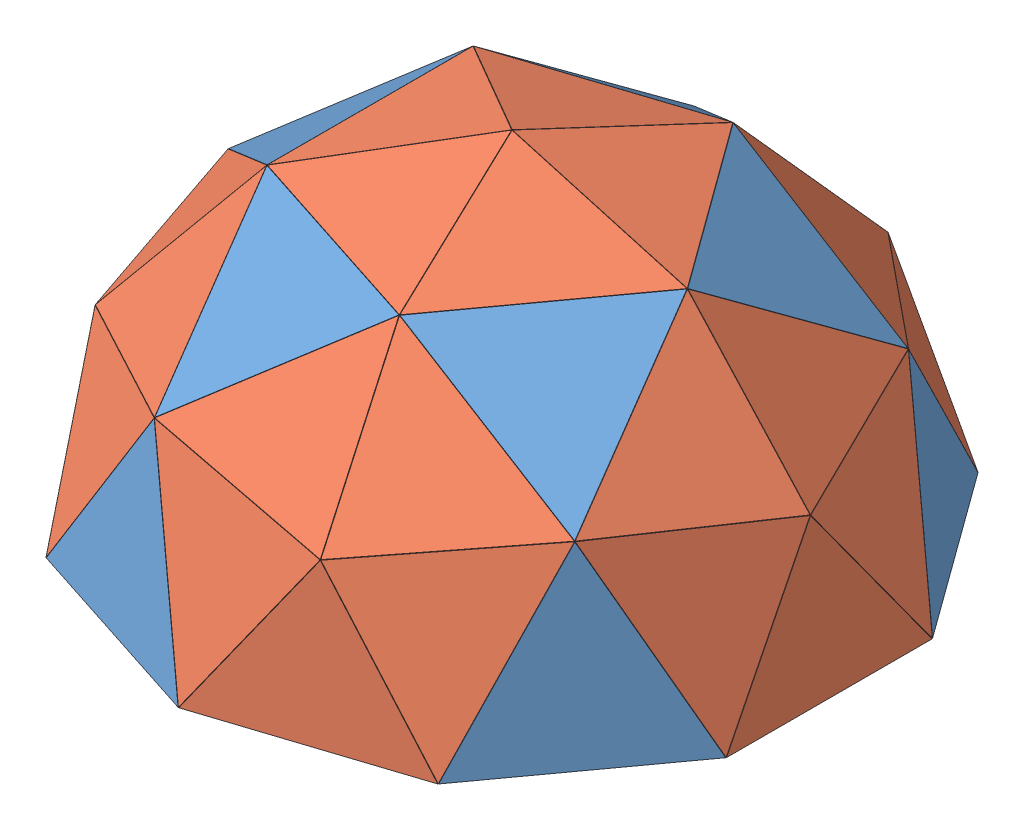
SolidWorks assembly AS_APPOLO1, configuration По умолчанию. Lengths in mm.
Overall size (616.24 389.86 611.38).
40 component instances, 2 part files, 25 mates.
Components (placement in the parent):
- d1^AS_APPOLO1-1: d1^AS_APPOLO1 [По умолчанию] at (-85.0651 52.5731 261.8034) x (-0.952822 -0.059759 -0.29759) z (0.303531 -0.187592 -0.934172) size (185.07 165.91 1) (virtual)
- d2^AS_APPOLO1-1: d2^AS_APPOLO1 [По умолчанию] at (75.8691 267.0702 55.1221) x (-0.963409 0.262502 0.054179) z (-0.268035 -0.943522 -0.194739) size (163.71 155.96 1) (virtual)
- d2^AS_APPOLO1-2: d2^AS_APPOLO1 [По умолчанию] at (-28.9794 267.0702 89.1894) x (-0.349237 0.262502 -0.899514) z (0.10238 -0.943522 -0.315094) size (163.71 155.96 1) (virtual)
- d2^AS_APPOLO1-3: d2^AS_APPOLO1 [По умолчанию] at (-93.7793 267.0702 0) x (0.747569 0.262502 -0.61011) z (0.331309 -0.943522 0) size (163.71 155.96 1) (virtual)
- d2^AS_APPOLO1-4: d2^AS_APPOLO1 [По умолчанию] at (-28.9794 267.0702 -89.1894) x (0.81126 0.262502 0.522446) z (0.10238 -0.943522 0.315094) size (163.71 155.96 1) (virtual)
- d2^AS_APPOLO1-5: d2^AS_APPOLO1 [По умолчанию] at (75.8691 267.0702 -55.1221) x (-0.246182 0.262502 0.932999) z (-0.268035 -0.943522 0.194739) size (163.71 155.96 1) (virtual)
- d1^AS_APPOLO1-2: d1^AS_APPOLO1 [По умолчанию] at (-275.2764 52.5731 0) x (-0.011413 -0.059759 -0.998148) z (0.982247 -0.187592 0) size (185.07 165.91 1) (virtual)
- d1^AS_APPOLO1-3: d1^AS_APPOLO1 [По умолчанию] at (-85.0651 52.5731 -261.8034) x (0.945768 -0.059759 -0.319299) z (0.303531 -0.187592 0.934172) size (185.07 165.91 1) (virtual)
- d1^AS_APPOLO1-4: d1^AS_APPOLO1 [По умолчанию] at (222.7033 52.5731 -161.8034) x (0.59593 -0.059759 0.80081) z (-0.794654 -0.187592 0.57735) size (185.07 165.91 1) (virtual)
- d1^AS_APPOLO1-5: d1^AS_APPOLO1 [По умолчанию] at (222.7033 52.5731 161.8034) x (-0.577463 -0.059759 0.814227) z (-0.794654 -0.187592 -0.57735) size (185.07 165.91 1) (virtual)
- d1^AS_APPOLO1-6: d1^AS_APPOLO1 [По умолчанию] at (-52.5731 222.7033 161.8034) x (0.964235 0.036933 0.262464) z (0.187592 -0.794654 -0.57735) size (185.07 165.91 1) (virtual)
- d2^AS_APPOLO1-6: d2^AS_APPOLO1 [По умолчанию] at (-7.0029 93.5175 267.0702) x (0.457316 0.843008 -0.283197) z (0.02474 -0.330384 -0.943522) size (163.71 155.96 1) (virtual)
- d2^AS_APPOLO1-7: d2^AS_APPOLO1 [По умолчанию] at (162.6454 93.5175 211.9481) x (-0.734672 -0.194973 0.649802) z (-0.574604 -0.330384 -0.748783) size (163.71 155.96 1) (virtual)
- d2^AS_APPOLO1-8: d2^AS_APPOLO1 [По умолчанию] at (86.7764 35.5587 267.0702) x (-0.611006 0.78604 0.093872) z (-0.306569 -0.125624 -0.943522) size (163.71 155.96 1) (virtual)
- d2^AS_APPOLO1-9: d2^AS_APPOLO1 [По умолчанию] at (10.9073 187.2968 211.9481) x (0.99391 -0.102798 0.039693) z (-0.038534 -0.661694 -0.748783) size (163.71 155.96 1) (virtual)
- d2^AS_APPOLO1-10: d2^AS_APPOLO1 [По умолчанию] at (115.7558 187.2968 177.8808) x (0.257221 -0.744305 0.616318) z (-0.408949 -0.661694 -0.628428) size (163.71 155.96 1) (virtual)
- d2^AS_APPOLO1-11: d2^AS_APPOLO1 [По умолчанию] at (-256.1629 93.5175 75.8691) x (0.410654 0.843008 0.347421) z (0.904988 -0.330384 -0.268035) size (163.71 155.96 1) (virtual)
- d2^AS_APPOLO1-12: d2^AS_APPOLO1 [По умолчанию] at (-151.3145 93.5175 -220.1806) x (-0.203517 0.843008 0.497914) z (0.534573 -0.330384 0.777868) size (163.71 155.96 1) (virtual)
- d2^AS_APPOLO1-13: d2^AS_APPOLO1 [По умолчанию] at (162.6454 93.5175 -211.9481) x (-0.536435 0.843008 -0.039693) z (-0.574604 -0.330384 0.748783) size (163.71 155.96 1) (virtual)
- d2^AS_APPOLO1-14: d2^AS_APPOLO1 [По умолчанию] at (251.8349 93.5175 89.1894) x (-0.128018 0.843008 -0.522446) z (-0.889698 -0.330384 -0.315094) size (163.71 155.96 1) (virtual)
- d2^AS_APPOLO1-15: d2^AS_APPOLO1 [По умолчанию] at (-227.1835 35.5587 165.0585) x (-0.278089 0.78604 -0.552094) z (0.802608 -0.125624 -0.583129) size (163.71 155.96 1) (virtual)
- d2^AS_APPOLO1-16: d2^AS_APPOLO1 [По умолчанию] at (-227.1835 35.5587 -165.0585) x (0.439138 0.78604 -0.435084) z (0.802608 -0.125624 0.583129) size (163.71 155.96 1) (virtual)
- d2^AS_APPOLO1-17: d2^AS_APPOLO1 [По умолчанию] at (86.7764 35.5587 -267.0702) x (0.549491 0.78604 0.283197) z (-0.306569 -0.125624 0.943522) size (163.71 155.96 1) (virtual)
- d2^AS_APPOLO1-18: d2^AS_APPOLO1 [По умолчанию] at (280.8143 35.5587 0) x (-0.099534 0.78604 0.61011) z (-0.992078 -0.125624 0) size (163.71 155.96 1) (virtual)
- d2^AS_APPOLO1-19: d2^AS_APPOLO1 [По умолчанию] at (-151.3145 93.5175 220.1806) x (-0.845025 -0.194973 -0.497914) z (0.534573 -0.330384 -0.777868) size (163.71 155.96 1) (virtual)
- d2^AS_APPOLO1-20: d2^AS_APPOLO1 [По умолчанию] at (-256.1629 93.5175 -75.8691) x (0.212418 -0.194973 -0.95753) z (0.904988 -0.330384 0.268035) size (163.71 155.96 1) (virtual)
- d2^AS_APPOLO1-21: d2^AS_APPOLO1 [По умолчанию] at (-7.0029 93.5175 -267.0702) x (0.976306 -0.194973 -0.093872) z (0.02474 -0.330384 0.943522) size (163.71 155.96 1) (virtual)
- d2^AS_APPOLO1-22: d2^AS_APPOLO1 [По умолчанию] at (251.8349 93.5175 -89.1894) x (0.390973 -0.194973 0.899514) z (-0.889698 -0.330384 0.315094) size (163.71 155.96 1) (virtual)
- d2^AS_APPOLO1-23: d2^AS_APPOLO1 [По умолчанию] at (-133.4042 187.2968 165.0585) x (-0.506667 -0.744305 0.435084) z (0.471299 -0.661694 -0.583129) size (163.71 155.96 1) (virtual)
- d2^AS_APPOLO1-24: d2^AS_APPOLO1 [По умолчанию] at (-198.2041 187.2968 -75.8691) x (-0.570359 -0.744305 -0.347421) z (0.700228 -0.661694 0.268035) size (163.71 155.96 1) (virtual)
- d2^AS_APPOLO1-25: d2^AS_APPOLO1 [По умолчанию] at (10.9073 187.2968 -211.9481) x (0.154166 -0.744305 -0.649802) z (-0.038534 -0.661694 0.748783) size (163.71 155.96 1) (virtual)
- d2^AS_APPOLO1-26: d2^AS_APPOLO1 [По умолчанию] at (204.9452 187.2968 -55.1221) x (0.665639 -0.744305 -0.054179) z (-0.724043 -0.661694 0.194739) size (163.71 155.96 1) (virtual)
- d2^AS_APPOLO1-27: d2^AS_APPOLO1 [По умолчанию] at (-198.2041 187.2968 75.8691) x (0.269385 -0.102798 0.95753) z (0.700228 -0.661694 -0.268035) size (163.71 155.96 1) (virtual)
- d2^AS_APPOLO1-28: d2^AS_APPOLO1 [По умолчанию] at (-133.4042 187.2968 -165.0585) x (-0.827421 -0.102798 0.552094) z (0.471299 -0.661694 0.583129) size (163.71 155.96 1) (virtual)
- d2^AS_APPOLO1-29: d2^AS_APPOLO1 [По умолчанию] at (115.7558 187.2968 -177.8808) x (-0.780759 -0.102798 -0.616318) z (-0.408949 -0.661694 0.628428) size (163.71 155.96 1) (virtual)
- d2^AS_APPOLO1-30: d2^AS_APPOLO1 [По умолчанию] at (204.9452 187.2968 55.1221) x (0.344885 -0.102798 -0.932999) z (-0.724043 -0.661694 -0.194739) size (163.71 155.96 1) (virtual)
- d1^AS_APPOLO1-7: d1^AS_APPOLO1 [По умолчанию] at (-170.1302 222.7033 0) x (0.048346 0.036933 0.998148) z (0.607062 -0.794654 0) size (185.07 165.91 1) (virtual)
- d1^AS_APPOLO1-8: d1^AS_APPOLO1 [По умолчанию] at (-52.5731 222.7033 -161.8034) x (-0.934355 0.036933 0.354425) z (0.187592 -0.794654 0.57735) size (185.07 165.91 1) (virtual)
- d1^AS_APPOLO1-9: d1^AS_APPOLO1 [По умолчанию] at (137.6382 222.7033 -100) x (-0.62581 0.036933 -0.779101) z (-0.491123 -0.794654 0.356822) size (185.07 165.91 1) (virtual)
- d1^AS_APPOLO1-10: d1^AS_APPOLO1 [По умолчанию] at (137.6382 222.7033 100) x (0.547583 0.036933 -0.835936) z (-0.491123 -0.794654 -0.356822) size (185.07 165.91 1) (virtual)
Mates (geometry in assembly coordinates):
- На месте1: in place: plane of ? through (-70.8876 43.8109 218.1695) normal (0.303531 -0.187592 -0.934172); moOrthogonalPlaneRef_w of ?; unknown of ?; unknown of d1^AS_APPOLO1-1
- Совпадение1: coincident aligned: plane of d1^AS_APPOLO1-1; plane of assembly
- Совпадение2: coincident aligned: plane of d1^AS_APPOLO1-1; moOrthogonalPlaneRef_w of assembly
- Совпадение3: coincident anti-aligned: plane of d1^AS_APPOLO1-1; moOrthogonalPlaneRef_w of assembly
- На месте2: in place: plane of ? through (63.2242 222.5585 45.9351) normal (-0.268035 -0.943522 -0.194739); unknown of ?; unknown of ?; unknown of d2^AS_APPOLO1-1
- Совпадение4: coincident aligned: plane of d2^AS_APPOLO1-1; plane of assembly
- Совпадение5: coincident aligned: plane of d2^AS_APPOLO1-1; moOrthogonalPlaneRef_w of assembly
- Совпадение6: coincident anti-aligned: plane of d2^AS_APPOLO1-1; moOrthogonalPlaneRef_w of assembly
- Совпадение8: coincident: point of d2^AS_APPOLO1-2; point of d1^AS_APPOLO1-6
- Совпадение11: coincident: point of d2^AS_APPOLO1-2; point of d1^AS_APPOLO1-6
- Совпадение12: coincident: point of d1^AS_APPOLO1-1; point of d1^AS_APPOLO1-6
- Совпадение13: coincident: point of d1^AS_APPOLO1-1; point of d2^AS_APPOLO1-6
- Совпадение15: coincident: point of d2^AS_APPOLO1-6; point of assembly
- Совпадение16: coincident: point of d2^AS_APPOLO1-7; point of assembly
- Совпадение17: coincident: point of d1^AS_APPOLO1-5; point of d2^AS_APPOLO1-7
- Совпадение18: coincident: point of d2^AS_APPOLO1-6; point of d2^AS_APPOLO1-7
- Совпадение23: coincident: point of d2^AS_APPOLO1-8; point of assembly
- Совпадение24: coincident: point of d2^AS_APPOLO1-8; point of assembly
- Совпадение25: coincident: point of d2^AS_APPOLO1-7; point of d2^AS_APPOLO1-8
- Совпадение26: coincident: point of d2^AS_APPOLO1-1; point of d2^AS_APPOLO1-9
- Совпадение27: coincident: point of d1^AS_APPOLO1-1; point of d2^AS_APPOLO1-9
- Совпадение28: coincident: point of d2^AS_APPOLO1-7; point of d2^AS_APPOLO1-9
- Совпадение29: coincident: point of d2^AS_APPOLO1-9; point of d2^AS_APPOLO1-10
- Совпадение30: coincident: point of d2^AS_APPOLO1-7; point of d2^AS_APPOLO1-10
- Совпадение31: coincident: point of d2^AS_APPOLO1-9; point of d2^AS_APPOLO1-10
